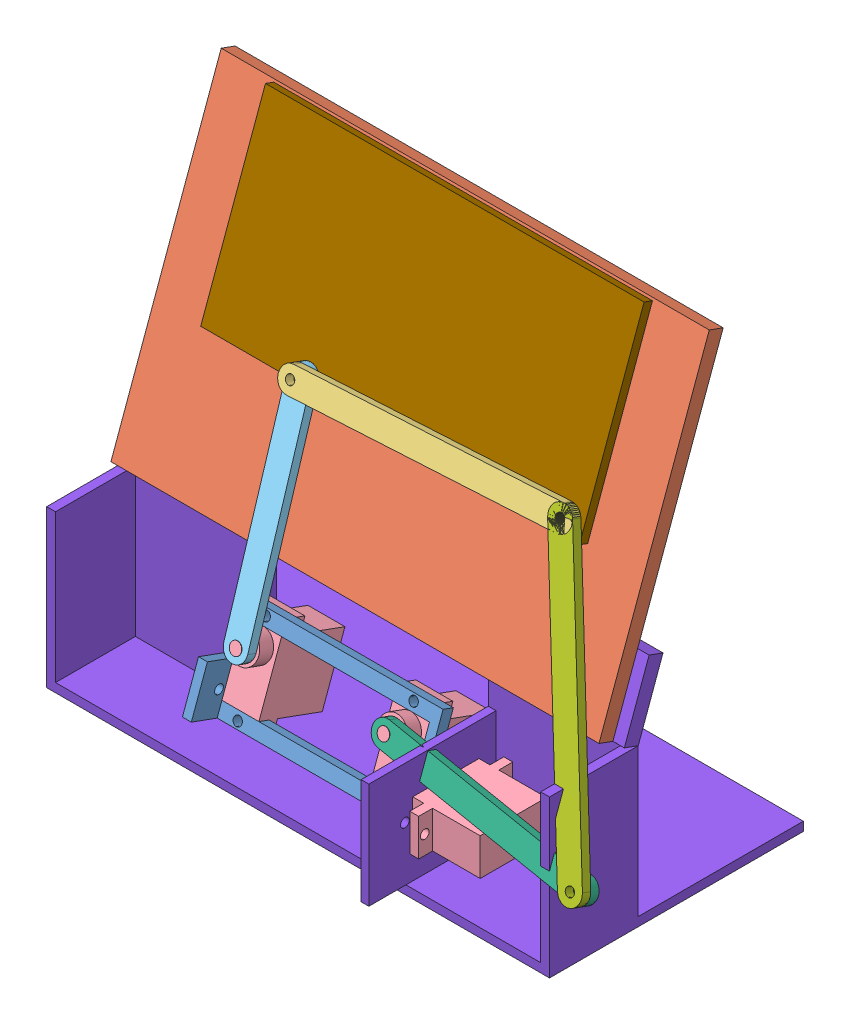
SolidWorks assembly V1, configuration 默认. Lengths in mm.
Overall size (185.1 159.11 101.82).
11 component instances, 9 part files, 25 mates.
Components (placement in the parent):
- l3-1: l3 [默认] at (58.46 -88.6414 -22.5308) x (1 0 0) z (0 -0.939693 0.34202) size (68.5 13 31.8)
- broad-1: broad [默认] at (56.4075 -25.8273 -49.7083) x (1 0 0) z (0 0.34202 0.939693) size (165 109 5)
- l1-1: l1 [默认] at (75.6862 -23.9515 -33.6251) x (-0.044141 0.938777 -0.341687) z (0 0.34202 0.939693) size (8 98 3)
- sg90-1: sg90 [默认] at (33.46 -107.9068 -35.8445) x (0 0.939693 -0.34202) z (1 0 0) size (31.8 30.9 12.5)
- l2-1: l2 [默认] at (32.095 -59.7084 -23.8032) x (0.999239 0.036648 -0.013339) z (0 0.34202 0.939693) size (8 78 3)
- sg90-2: sg90 [默认] at (83.46 -107.9068 -35.8445) x (0 0.939693 -0.34202) z (1 0 0) size (31.8 30.9 12.5)
- l4-1: l4 [默认] at (118.0886 -96.3253 -7.2832) x (0.1453 0.92972 -0.33839) z (0 -0.34202 -0.939693) size (8 78 3)
- l5-1: l5 [默认] at (136.6797 -60.5685 -17.1051) x (0.934338 0.334894 -0.121892) z (0 -0.34202 -0.939693) size (8 98 3)
- base-1: base [默认] at (57.7785 -128.7506 -20.7667) size (170 77.71 101.82)
- sg90-3: sg90 [默认] at (120.51 -106.914 -15.8014) x (0 0 1) z (0 -1 0) size (31.8 30.9 12.5)
- write-1: write [默认] at (55.9728 -3.7417 -52.4259) x (1 0 0) z (0 0.34202 0.939693) size (128 64 3)
Mates (geometry in assembly coordinates):
- 同心1: concentric: cylinder of assembly; cylinder of assembly; cylinder of l3-1 through (33.46 -87.094 -19.1565) axis (0 -0.34202 -0.939693) radius 1.5; cylinder of sg90-1 through (33.46 -88.3595 -22.6334) axis (0 -0.34202 -0.939693) radius 1.5
- 重合1: coincident: plane of assembly; plane of assembly; plane of l3-1 through (58.46 -88.6414 -22.5308) normal (0 -0.34202 -0.939693); plane of sg90-1 through (33.46 -101.3743 -17.8964) normal (0 0.34202 0.939693)
- 同心2: concentric: cylinder of assembly; cylinder of assembly; cylinder of l3-1 through (83.46 -87.094 -19.1565) axis (0 -0.34202 -0.939693) radius 1.5; cylinder of sg90-2 through (83.46 -88.3595 -22.6334) axis (0 -0.34202 -0.939693) radius 1.5
- 重合2: coincident: plane of assembly; plane of assembly; plane of l3-1 through (58.46 -88.6414 -22.5308) normal (0 -0.34202 -0.939693); plane of sg90-2 through (83.46 -101.3743 -17.8964) normal (0 0.34202 0.939693)
- 同心9: concentric: cylinder of assembly; cylinder of assembly; cylinder of sg90-1 through (33.46 -91.5123 -8.9286) axis (0 -0.34202 -0.939693) radius 2; cylinder of l2-1 through (33.46 -92.5726 -11.8416) axis (0 0.34202 0.939693) radius 1.5
- 重合5: coincident: plane of assembly; plane of assembly; plane of sg90-1 through (33.46 -92.5726 -11.8416) normal (0 0.34202 0.939693); plane of l2-1 through (32.095 -59.7084 -23.8032) normal (0 -0.34202 -0.939693)
- 重合6: coincident: plane of assembly; plane of assembly; plane of l1-1 through (75.6862 -23.9515 -33.6251) normal (0 -0.34202 -0.939693); plane of l2-1 through (32.095 -58.6823 -20.9841) normal (0 0.34202 0.939693)
- 同心10: concentric: cylinder of assembly; cylinder of assembly; cylinder of l1-1 through (30.73 -25.8181 -32.9457) axis (0 0.34202 0.939693) radius 1.5; cylinder of l2-1 through (30.73 -26.8441 -35.7648) axis (0 0.34202 0.939693) radius 1.5
- 重合7: coincident: plane of assembly; plane of assembly; plane of sg90-2 through (83.46 -92.5726 -11.8416) normal (0 0.34202 0.939693); plane of l4-1 through (118.0886 -97.3514 -10.1023) normal (0 -0.34202 -0.939693)
- 同心11: concentric: circle of assembly; cylinder of assembly; circle of sg90-2; cylinder of l4-1 through (83.46 -91.5465 -9.0225) axis (0 -0.34202 -0.939693) radius 1.5
- 重合8: coincident: plane of assembly; plane of assembly; plane of l4-1 through (118.0886 -96.3253 -7.2832) normal (0 0.34202 0.939693); plane of l5-1 through (136.6797 -61.5946 -19.9241) normal (0 -0.34202 -0.939693)
- 同心12: concentric: cylinder of assembly; cylinder of assembly; cylinder of l4-1 through (152.7171 -101.1042 -5.5438) axis (0 -0.34202 -0.939693) radius 1.5; cylinder of l5-1 through (152.7171 -100.0781 -2.7247) axis (0 -0.34202 -0.939693) radius 1.5
- 同心13: concentric: cylinder of assembly; cylinder of assembly; cylinder of l1-1 through (120.6423 -22.085 -34.3045) axis (0 0.34202 0.939693) radius 1.5; cylinder of l5-1 through (120.6423 -21.0589 -31.4854) axis (0 -0.34202 -0.939693) radius 1.5
- 重合9: coincident: plane of assembly; plane of assembly; plane of broad-1 through (56.4075 -25.8273 -49.7083) normal (0 -0.34202 -0.939693); plane of base-1 through (57.7785 -126.0126 -13.2439) normal (0 0.34202 0.939693)
- 重合10: coincident: plane of assembly; plane of assembly; plane of broad-1 through (-26.0925 -75.3304 -26.3698) normal (0 -0.939693 0.34202); plane of base-1 through (142.7785 -77.0405 -31.0682) normal (0 -0.939693 0.34202)
- 同心15: concentric: cylinder of assembly; cylinder of assembly; cylinder of l3-1 through (33.46 -113.1235 -9.6826) axis (0 -0.34202 -0.939693) radius 1.5; cylinder of sg90-1 through (33.46 -114.389 -13.1594) axis (0 -0.34202 -0.939693) radius 1.5
- 同心16: concentric: cylinder of assembly; cylinder of assembly; cylinder of l3-1 through (83.46 -113.1235 -9.6826) axis (0 -0.34202 -0.939693) radius 1.5; cylinder of sg90-2 through (83.46 -114.389 -13.1594) axis (0 -0.34202 -0.939693) radius 1.5
- 重合11: coincident: plane of assembly; plane of assembly; plane of l3-1 through (92.71 -88.6414 -22.5308) normal (1 0 0); plane of sg90-3 through (92.71 -106.914 -9.6014) normal (-1 0 0)
- 同心17: concentric: cylinder of assembly; cylinder of assembly; cylinder of l3-1 through (79.71 -106.914 -9.6014) axis (1 0 0) radius 1.5; cylinder of sg90-3 through (89.61 -106.914 -9.6014) axis (1 0 0) radius 2
- 重合12: coincident: plane of assembly; plane of assembly; plane of base-1 through (97.71 -89.5204 10.2333) normal (1 0 0); plane of sg90-3 through (97.71 -106.914 -15.8014) normal (-1 0 0)
- 同心18: concentric: cylinder of assembly; cylinder of assembly; cylinder of base-1 through (84.71 -106.914 -1.9514) axis (1 0 0) radius 1.5; cylinder of sg90-3 through (101.41 -106.914 -1.9514) axis (1 0 0) radius 1.5
- 同心19: concentric: cylinder of assembly; cylinder of assembly; cylinder of base-1 through (84.71 -106.914 -29.6514) axis (1 0 0) radius 1.5; cylinder of sg90-3 through (101.41 -106.914 -29.6514) axis (1 0 0) radius 1.5
- 平行2: parallel: plane of assembly; plane of assembly; plane of l5-1 through (136.6797 -61.5946 -19.9241) normal (0 -0.34202 -0.939693); plane of base-1 through (57.7785 -126.0126 -13.2439) normal (0 0.34202 0.939693)
- 重合15: coincident: plane of assembly; plane of assembly; plane of broad-1 through (56.4075 -24.1172 -45.0099) normal (0 0.34202 0.939693); plane of write-1 through (55.9728 -3.7417 -52.4259) normal (0 -0.34202 -0.939693)
- 平行3: parallel: plane of assembly; line of assembly; plane of broad-1 through (-26.0925 27.0961 -63.65) normal (0 0.939693 -0.34202); line of write-1 through (119.9728 27.3545 -60.5515) axis (-1 0 0)
